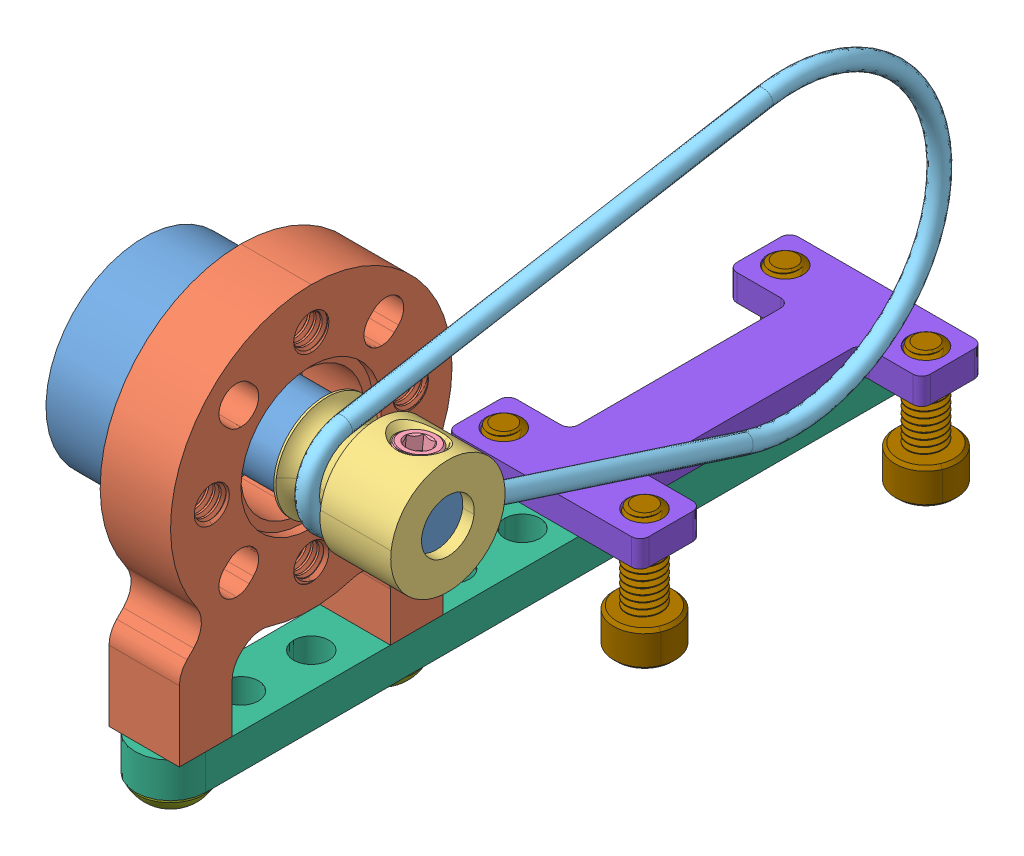
SolidWorks assembly Encoder1_Assembly, configuration Default. Lengths in mm.
Overall size (37.07 52.88 88).
15 component instances, 9 part files, 29 mates.
Components (placement in the parent):
- 6127V1A360L.5 Non-Contacting Hall Effect-1: 6127V1A360L.5 Non-Contacting Hall Effect [Default] at origin size (35.77 22.23 22.23)
- 1200-0024-0001-1: 1200-0024-0001 [Default] at (-5.59 0 0) x (0 0 -1) z (0 -1 0) size (32 8.01 40)
- 3401-0006-0008 assembly-1: 3401-0006-0008 assembly [Default] at (9.8045 -33.6703 -35.941) x (0 -0.118935 -0.992902) z (1 0 0) size (13 13.01 14)
  - 3401-0006-0008 assembly.STEP-1: 3401-0006-0008 assembly.STEP [Default] at origin size (13 13.01 14)
    - 3401-0006-0008.STEP-1: 3401-0006-0008.STEP [Default] at (-39.6905 29.1567 8.1355) size (13 13.01 14)
    - 2806-0005-0004_91390A117.STEP-1: 2806-0005-0004_91390A117.STEP [Default] at (-39.6905 33.4996 4.1145) x (0.999377 0 0.035289) z (0 1 0) size (5.01 5.01 4.01)
- Round_Belt-1: Round_Belt [Default] at (6.94 0 0) x (0 -0.07 -0.997547) z (-1 0 0) size (74 36 2)
- 1102-0011-0088-1: 1102-0011-0088 [Default] at (-1.59 -28 -28) x (0 0 1) z (-1 0 0) size (88 4 8)
- 2802-0004-0008-1: 2802-0004-0008 [Default] at (-1.59 -30.2 -12) x (1 0 0) z (0 -1 0) size (7.6 7.6 10.21)
- 2802-0004-0008-2: 2802-0004-0008 [Default] at (-1.59 -30.2 12) x (1 0 0) z (0 -1 0) size (7.6 7.6 10.21)
- 2803-0039-0022-1: 2803-0039-0022 [Default] at (-1.59 -24 -49.8773) x (0 0 -1) z (1 0 0) size (39 18.7 22)
- 2800-0004-0010-1: 2800-0004-0010 [Default] at (-9.59 -20.5 -33.8773) x (-0.920421 0 -0.390928) z (0 1 0) size (7 7 14.01)
- 2800-0004-0010-2: 2800-0004-0010 [Default] at (6.41 -20.5 -33.8773) x (-0.920421 0 -0.390928) z (0 1 0) size (7 7 14.01)
- 2800-0004-0010-3: 2800-0004-0010 [Default] at (6.41 -20.5 -65.8773) x (-0.920421 0 -0.390928) z (0 1 0) size (7 7 14.01)
- 2800-0004-0010-4: 2800-0004-0010 [Default] at (-9.59 -20.5 -65.8773) x (-0.920421 0 -0.390928) z (0 1 0) size (7 7 14.01)
Mates (geometry in assembly coordinates):
- Coincident1: coincident aligned: plane of 6127V1A360L.5 Non-Contacting Hall Effect-1 through (0 0 0) normal (0 0 1)
- Coincident2: coincident aligned: plane of 6127V1A360L.5 Non-Contacting Hall Effect-1 through (0 0 0) normal (1 0 0)
- Coincident3: coincident aligned: plane of 6127V1A360L.5 Non-Contacting Hall Effect-1 through (0 0 0) normal (0 1 0)
- Concentric1: concentric aligned: cylinder of 6127V1A360L.5 Non-Contacting Hall Effect-1 through (-16.64 0 0) axis (-1 0 0) radius 11.115; cylinder of 1200-0024-0001-1 through (2.41 0 0) axis (-1 0 0) radius 7
- Coincident4: coincident anti-aligned: plane of 6127V1A360L.5 Non-Contacting Hall Effect-1 through (-5.59 11.115 0) normal (1 0 0); plane of 1200-0024-0001-1 through (-5.59 0 0) normal (-1 0 0)
- Concentric2: concentric anti-aligned: cylinder of 6127V1A360L.5 Non-Contacting Hall Effect-1 through (-16.64 0 0) axis (-1 0 0) radius 3.175; cylinder of 3401-0006-0008 assembly-1/3401-0006-0008 assembly.STEP-1/3401-0006-0008.STEP-1 through (17.94 0 0) axis (1 0 0) radius 6.5
- Coincident5: coincident aligned: plane of 6127V1A360L.5 Non-Contacting Hall Effect-1 through (3.94 3.175 0) normal (1 0 0); circle of 3401-0006-0008 assembly-1/3401-0006-0008 assembly.STEP-1/3401-0006-0008.STEP-1
- Concentric3: concentric anti-aligned: circle of 3401-0006-0008 assembly-1/3401-0006-0008 assembly.STEP-1/3401-0006-0008.STEP-1; circle of Round_Belt-1
- Coincident6: coincident anti-aligned: circle of 3401-0006-0008 assembly-1/3401-0006-0008 assembly.STEP-1/3401-0006-0008.STEP-1; plane of Round_Belt-1 through (6.94 0 0) normal (-1 0 0)
- Parallel1: parallel anti-aligned: line of assembly; plane of 1200-0024-0001-1 through (-21.0092 -24 0) normal (0 -1 0)
- Distance2: distance = 20.5 mm: point of Round_Belt-1; plane of 1200-0024-0001-1 through (-21.0092 -24 0) normal (0 -1 0)
- Coincident10: coincident aligned: circle of 1200-0024-0001-1; cylinder of 1102-0011-0088-1 through (-1.59 -24 12) axis (0 1 0) radius 2
- Coincident11: coincident anti-aligned: plane of 1200-0024-0001-1 through (-21.0092 -24 0) normal (0 -1 0); plane of 1102-0011-0088-1 through (-1.59 -24 -68) normal (0 1 0)
- Parallel2: parallel anti-aligned: plane of 1200-0024-0001-1 through (2.41 0 0) normal (1 0 0); plane of 1102-0011-0088-1 through (-5.59 -24 -68) normal (-1 0 0)
- Concentric4: concentric anti-aligned: cylinder of 1102-0011-0088-1 through (-1.59 -24 12) axis (0 1 0) radius 2; cylinder of 2802-0004-0008-2 through (-1.59 -30.2 12) axis (0 -1 0) radius 3.8
- Coincident13: coincident anti-aligned: plane of 1102-0011-0088-1 through (-1.59 -28 -68) normal (0 -1 0); plane of 2802-0004-0008-2 through (-1.59 -28 8.2) normal (0 1 0)
- Coincident14: coincident anti-aligned: plane of 1102-0011-0088-1 through (-1.59 -28 -68) normal (0 -1 0); plane of 2802-0004-0008-1 through (-1.59 -28 -15.8) normal (0 1 0)
- Concentric5: concentric anti-aligned: cylinder of 1102-0011-0088-1 through (-1.59 -24 -12) axis (0 1 0) radius 2; cylinder of 2802-0004-0008-1 through (-1.59 -30.2 -12) axis (0 -1 0) radius 3.8
- Coincident15: coincident anti-aligned: plane of 1102-0011-0088-1 through (-1.59 -24 -68) normal (0 1 0); plane of 2803-0039-0022-1 through (-1.59 -24 -49.8773) normal (0 -1 0)
- Coincident20: coincident: point of Round_Belt-1; plane of 2803-0039-0022-1 through (-1.59 -24 -49.8773) normal (0 0 -1)
- Coincident21: coincident aligned: plane of 1102-0011-0088-1 through (-5.59 -24 -68) normal (-1 0 0); plane of 2803-0039-0022-1 through (-5.59 -21 -49.8773) normal (-1 0 0)
- Concentric6: concentric aligned: circle of 2803-0039-0022-1; cylinder of 2800-0004-0010-1 through (-9.59 -34.5 -33.8773) axis (0 1 0) radius 3.5
- Distance3: distance = 2.5 mm anti-aligned: plane of 1102-0011-0088-1 through (-1.59 -28 -68) normal (0 -1 0); plane of 2800-0004-0010-1 through (-9.59 -30.5 -33.8773) normal (0 1 0)
- Concentric7: concentric aligned: circle of 2803-0039-0022-1; cylinder of 2800-0004-0010-4 through (-9.59 -34.5 -65.8773) axis (0 1 0) radius 3.5
- Concentric8: concentric aligned: circle of 2803-0039-0022-1; cylinder of 2800-0004-0010-3 through (6.41 -34.5 -65.8773) axis (0 1 0) radius 3.5
- Concentric9: concentric aligned: circle of 2803-0039-0022-1; cylinder of 2800-0004-0010-2 through (6.41 -34.5 -33.8773) axis (0 1 0) radius 3.5
- Coincident24: coincident aligned: plane of 2800-0004-0010-1 through (-9.59 -34.5 -33.8773) normal (0 -1 0); plane of 2800-0004-0010-2 through (6.41 -34.5 -33.8773) normal (0 -1 0)
- Coincident25: coincident aligned: plane of 2800-0004-0010-1 through (-9.59 -34.5 -33.8773) normal (0 -1 0); plane of 2800-0004-0010-3 through (6.41 -34.5 -65.8773) normal (0 -1 0)
- Coincident26: coincident aligned: plane of 2800-0004-0010-3 through (6.41 -34.5 -65.8773) normal (0 -1 0); plane of 2800-0004-0010-4 through (-9.59 -34.5 -65.8773) normal (0 -1 0)
